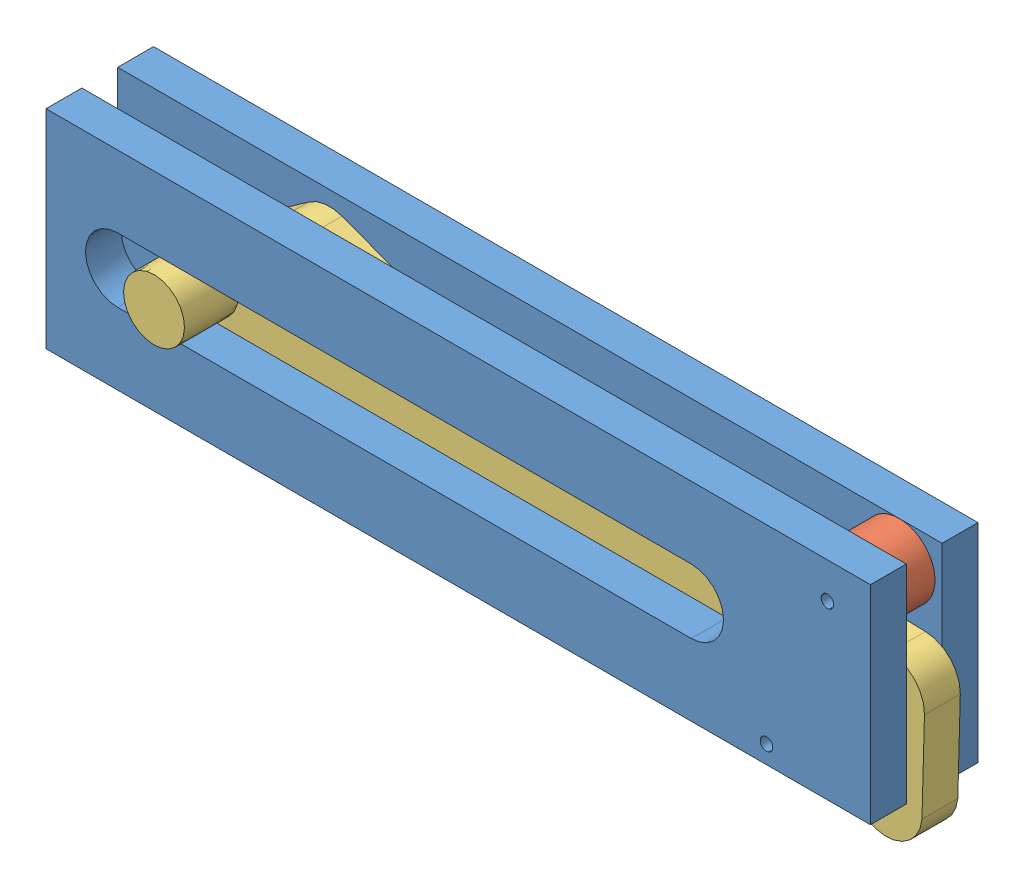
SolidWorks assembly bras_pousseur, configuration Défaut. Lengths in mm.
Overall size (235.74 68.91 40).
5 component instances, 3 part files, 12 mates.
Components (placement in the parent):
- guide-1: guide [Défaut] at (-12.817 43.31 0) size (230 58 10)
- guide-2: guide [Défaut] at (-12.817 43.31 -20) size (230 58 10)
- roue-1: roue [Défaut] at (53.8956 20.2884 -10) x (-0.641153 0.767413 0) z (0 0 1) size (20 20 10)
- roue-2: roue [Défaut] at (70.8956 63.2884 -10) size (20 20 10)
- bras-2: bras [Défaut] at (-3.3476 62.0801 0) x (0.999633 -0.027076 0) z (0 0 -1) size (210 60.09 40)
Mates (geometry in assembly coordinates):
- Coïncidente11: coincident aligned: plane of guide-1 through (-147.1044 73.2884 10) normal (-1 0 0); plane of guide-2 through (-147.1044 73.2884 -10) normal (-1 0 0)
- Coïncidente12: coincident aligned: plane of guide-1 through (-147.1044 15.2884 10) normal (0 -1 0); plane of guide-2 through (-147.1044 15.2884 -10) normal (0 -1 0)
- Coaxiale3: concentric aligned: cylinder of guide-1 through (53.8956 20.2884 10) axis (0 0 -1) radius 1.75; cylinder of roue-1 through (53.8956 20.2884 0) axis (0 0 -1) radius 1.5
- Coïncidente15: coincident anti-aligned: plane of guide-1 through (-147.1044 15.2884 0) normal (0 0 -1); plane of roue-2 through (70.8956 63.2884 0) normal (0 0 1)
- Coaxiale4: concentric aligned: cylinder of guide-1 through (70.8956 63.2884 10) axis (0 0 -1) radius 1.75; cylinder of roue-2 through (70.8956 63.2884 0) axis (0 0 -1) radius 1.5
- Distance1: distance = 10.5 mm anti-aligned: plane of guide-1 through (-147.1044 15.2884 0) normal (0 0 -1); plane of guide-2 through (-147.1044 15.2884 -10.5) normal (0 0 1)
- Coïncidente17: coincident anti-aligned: plane of guide-1 through (-147.1044 15.2884 0) normal (0 0 -1); plane of roue-1 through (53.8956 20.2884 0) normal (0 0 1)
- Coïncidente18: coincident anti-aligned: plane of guide-1 through (-147.1044 15.2884 0) normal (0 0 -1); plane of bras-2 through (60.4385 37.2651 0) normal (0 0 1)
- ContrainteCameTangente1: cam tangent: cylinder of guide-1 through (32.8956 44.2884 10) axis (0 0 -1) radius 9; plane of guide-1 through (-127.1044 53.2884 10) normal (0 -1 0); cylinder of guide-1 through (-127.1044 44.2884 10) axis (0 0 -1) radius 9; plane of guide-1 through (32.8956 35.2884 10) normal (0 1 0); cylinder of bras-2 through (-111.9708 44.7884 15) axis (0 0 -1) radius 8.5
- Coïncidente19: coincident anti-aligned: plane of guide-1 through (-147.1044 15.2884 0) normal (0 0 -1); plane of bras-2 through (-88.0415 59.2285 0) normal (0 0 1)
- Distance2: distance = 10 mm anti-aligned: plane of guide-1 through (-147.1044 15.2884 0) normal (0 0 -1); plane of guide-2 through (-147.1044 15.2884 -10) normal (0 0 1)
- Tangent1: tangent anti-aligned: cylinder of roue-1 through (53.8956 20.2884 0) axis (0 0 -1) radius 10; plane of bras-2 through (-112.2416 34.7921 -10) normal (-0.027076 -0.999633 0)
